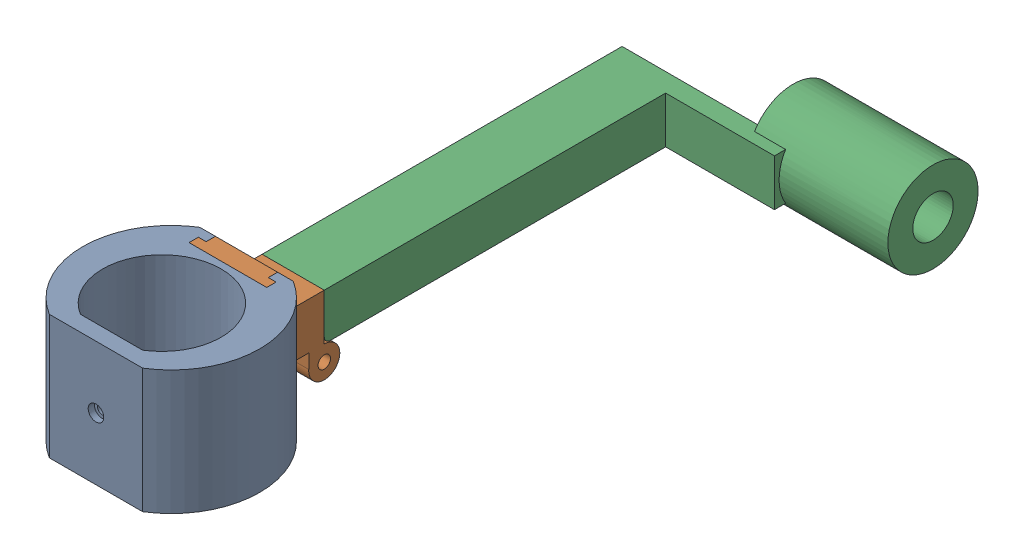
SolidWorks assembly lens_collar_hinge_assy_1, configuration Default. Lengths in mm.
Overall size (108.48 40 203.73).
3 component instances, 3 part files, 0 mates.
Components (placement in the parent):
- len_mount_hinge1_1-1: len_mount_hinge1_1 [Default] at origin size (56.97 40 48.43)
- len_mount_hinge2_1-1: len_mount_hinge2_1 [Default] at (0 0 -27.2143) x (0 0 -1) z (1 0 0) size (26 37.5 25)
- len_mount_hinge3_1-1: len_mount_hinge3_1 [Default] at (0 0 -42.2143) x (0 0 -1) z (1 0 0) size (145.3 32 90)
